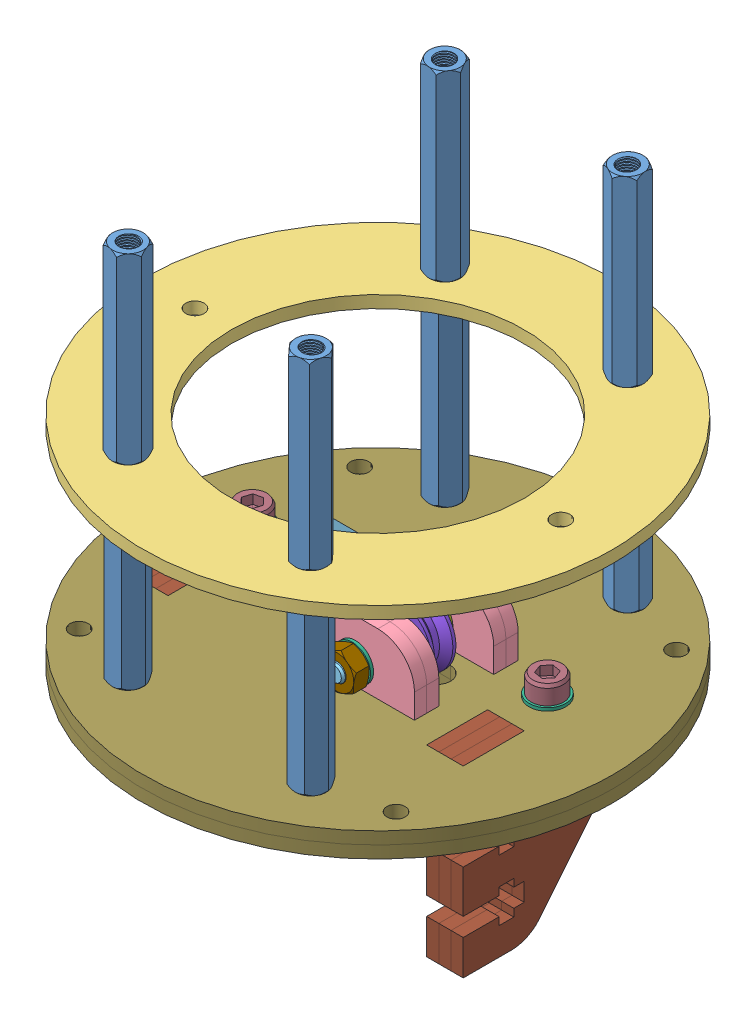
SolidWorks assembly RobotBaseStdServo, configuration Default. Lengths in mm.
Overall size (77 92.39 77).
48 component instances, 14 part files, 113 mates.
Components (placement in the parent):
- M3Spacer30-1: M3Spacer30 [Default] at (-2388.5733 91.3509 1101.0133) size (6.28 30.59 5)
- M3ThreadRod-1: M3ThreadRod [Default] at (-2388.5733 111.8509 1101.0133) x (0.999973 0 0.007408) z (-0.007408 0 0.999973) size (3.13 20.14 3.46)
- MiddlePlate-1: MiddlePlate [Default] at (-2373.5733 123.3509 1075.0326) x (1 0 0) z (0 -1 0) size (77 77 2)
- M3ThreadRod-2: M3ThreadRod [Default] at (-2388.5733 111.8509 1049.0518) x (0.846012 0 -0.533163) z (0.533163 0 0.846012) size (3.13 20.14 3.46)
- M3ThreadRod-3: M3ThreadRod [Default] at (-2358.5733 111.8509 1049.0518) x (-0.305342 0 -0.952243) z (0.952243 0 -0.305342) size (3.13 20.14 3.46)
- M3ThreadRod-4: M3ThreadRod [Default] at (-2358.5733 111.8509 1101.0133) x (0.427939 0 -0.903808) z (0.903808 0 0.427939) size (3.13 20.14 3.46)
- M3Spacer30-2: M3Spacer30 [Default] at (-2358.5733 91.3509 1049.0518) x (0.746598 0 -0.665276) z (0.665276 0 0.746598) size (6.28 30.59 5)
- M3Spacer30-3: M3Spacer30 [Default] at (-2388.5733 91.3509 1049.0518) size (6.28 30.59 5)
- M3Spacer30-4: M3Spacer30 [Default] at (-2358.5733 91.3509 1101.0133) size (6.28 30.59 5)
- M3Spacer30-5: M3Spacer30 [Default] at (-2388.5733 123.3509 1049.0518) x (0.415568 0 0.909562) z (-0.909562 0 0.415568) size (6.28 30.59 5)
- M3Spacer30-6: M3Spacer30 [Default] at (-2358.5733 123.3509 1049.0518) x (0.108158 0 0.994134) z (-0.994134 0 0.108158) size (6.28 30.59 5)
- M3Spacer30-7: M3Spacer30 [Default] at (-2358.5733 123.3509 1101.0133) x (0.980096 0 -0.198526) z (0.198526 0 0.980096) size (6.28 30.59 5)
- M3Spacer30-8: M3Spacer30 [Default] at (-2388.5733 123.3509 1101.0133) x (0.67609 0 -0.736819) z (0.736819 0 0.67609) size (6.28 30.59 5)
- BearingBase-1: BearingBase [Default] at (-2368.7733 94.8509 1083.5326) x (-1 0 0) z (0 0 -1) size (19.4 14 2)
- BearingBase-2: BearingBase [Default] at (-2368.7733 94.8509 1081.5326) x (-1 0 0) z (0 0 -1) size (19.4 14 2)
- BearingBase-3: BearingBase [Default] at (-2368.7733 94.8509 1066.5326) size (19.4 14 2)
- BearingBase-4: BearingBase [Default] at (-2368.7733 94.8509 1068.5326) size (19.4 14 2)
- M3x20-1: M3x20 [Default] at (-2368.7733 94.8509 1066.5326) x (0.029389 0.999568 0) z (-0.999568 0.029389 0) size (5.5 23.77 5.5)
- M3Washer-1: M3Washer [Default] at (-2368.7733 94.8509 1077.5326) x (-0.205267 0.978706 0) z (-0.978706 -0.205267 0) size (6 0.5 6)
- PlasticSpacer-1: PlasticSpacer [Default] at (-2368.7733 94.8509 1070.5326) x (-0.999639 0.026866 0) z (0.026866 0.999639 0) size (6 2 6)
- pulley-1: pulley [Default] at (-2368.7733 94.8509 1073.0326) x (0.617179 0.786823 0) z (0.786823 -0.617179 0) size (12 4 12)
- M3Washer-2: M3Washer [Default] at (-2368.7733 94.8509 1073.0326) x (0.250287 -0.968172 0) z (0.968172 0.250287 0) size (6 0.5 6)
- PlasticSpacer-3: PlasticSpacer [Default] at (-2368.7733 94.8509 1079.5326) x (0.027413 -0.999624 0) z (0.999624 0.027413 0) size (6 2 6)
- M3Nut-1: M3Nut [Default] at (-2368.7733 94.8509 1084.0326) x (-0.925416 -0.378953 0) z (-0.378953 0.925416 0) size (6.35 2.7 5.5)
- M3Washer-4: M3Washer [Default] at (-2388.5733 87.3509 1049.0518) x (-1 0 0) z (0 0 1) size (6 0.5 6)
- M3x10-1: M3x10 [Default] at (-2388.5733 86.8509 1049.0518) x (0.341572 0 -0.939856) z (-0.939856 0 -0.341572) size (5.5 13.21 5.5)
- M3x10-2: M3x10 [Default] at (-2358.5733 86.8509 1049.0518) x (-0.021144 0 0.999776) z (0.999776 0 0.021144) size (5.5 13.21 5.5)
- M3x10-3: M3x10 [Default] at (-2388.5733 86.8509 1101.0133) x (-0.638743 0 0.76942) z (0.76942 0 0.638743) size (5.5 13.21 5.5)
- M3x10-4: M3x10 [Default] at (-2358.5733 86.8509 1101.0133) x (-0.799312 0 0.600916) z (0.600916 0 0.799312) size (5.5 13.21 5.5)
- M3Washer-5: M3Washer [Default] at (-2358.5733 87.3509 1101.0133) x (-1 0 0) z (0 0 1) size (6 0.5 6)
- M3Washer-6: M3Washer [Default] at (-2358.5733 87.3509 1049.0518) x (-1 0 0) z (0 0 1) size (6 0.5 6)
- M3Washer-7: M3Washer [Default] at (-2388.5733 87.3509 1101.0133) x (-1 0 0) z (0 0 1) size (6 0.5 6)
- M3Washer-8: M3Washer [Default] at (-2368.7733 94.8509 1084.0326) x (1 0 0) z (0 1 0) size (6 0.5 6)
- stdServoBase-1: stdServoBase [Default] at (-2350.5733 61.2509 1086.0326) x (0 0 -1) z (1 0 0) size (23 30.1 2)
- stdServoBase-2: stdServoBase [Default] at (-2354.5733 61.2509 1086.0326) x (0 0 -1) z (1 0 0) size (23 30.1 2)
- stdServoBase-3: stdServoBase [Default] at (-2352.5733 61.2509 1086.0326) x (0 0 -1) z (1 0 0) size (23 30.1 2)
- stdServoBase-4: stdServoBase [Default] at (-2398.9733 61.2509 1086.0326) x (0 0 -1) z (1 0 0) size (23 30.1 2)
- M3Nut-2: M3Nut [Default] at (-2351.5733 80.9509 1069.2266) x (-1 0 0) z (0 0 -1) size (6.35 2.7 5.5)
- M3Nut-5: M3Nut [Default] at (-2399.9733 83.4509 1069.2266) x (1 0 0) z (0 0 -1) size (6.35 2.7 5.5)
- M3Washer-13: M3Washer [Default] at (-2351.5733 91.3509 1069.2266) size (6 0.5 6)
- M3Washer-14: M3Washer [Default] at (-2399.9733 91.3509 1069.2266) size (6 0.5 6)
- BottomPlateStdServo-2: BottomPlateStdServo [Default] at (-2373.6467 89.3509 1075.0326) x (1 0 0) z (0 1 0) size (77 77 2)
- BottomPlateStdServo-3: BottomPlateStdServo [Default] at (-2373.6467 87.3509 1075.0326) x (1 0 0) z (0 1 0) size (77 77 2)
- stdServoBase-7: stdServoBase [Default] at (-2402.9733 61.2509 1086.0326) x (0 0 -1) z (1 0 0) size (23 30.1 2)
- stdServoBase-8: stdServoBase [Default] at (-2400.9733 61.2509 1086.0326) x (0 0 -1) z (1 0 0) size (23 30.1 2)
- M3x12-11: M3x12 [Default] at (-2351.5733 94.3509 1069.2266) x (0 -1 0) z (0.637805 0 -0.770198) size (15.11 5.3 5.3)
- M3x12-12: M3x12 [Default] at (-2399.9733 94.3509 1069.2266) x (0 -1 0) z (0.678502 0 0.734599) size (15.11 5.3 5.3)
- PCBMount-1: PCBMount [Default] at (-2380.5233 80.3509 1061.5326) x (-1 0 0) z (0 0 1) size (31.5 14 2)
Mates (geometry in assembly coordinates):
- Concentric1: concentric anti-aligned: circle of M3Spacer30-1; circle of MiddlePlate-1
- Concentric2: concentric anti-aligned: circle of MiddlePlate-1; circle of M3Spacer30-4
- Concentric3: concentric anti-aligned: circle of MiddlePlate-1; circle of M3Spacer30-3
- Concentric4: concentric anti-aligned: circle of MiddlePlate-1; circle of M3Spacer30-2
- Concentric5: concentric aligned: circle of M3ThreadRod-4; circle of M3Spacer30-4
- Concentric7: concentric anti-aligned: circle of M3ThreadRod-3; circle of M3Spacer30-2
- Concentric8: concentric aligned: circle of M3ThreadRod-2; circle of M3Spacer30-3
- Concentric9: concentric aligned: circle of M3Spacer30-1; circle of M3ThreadRod-1
- Distance5: distance = 10 mm aligned: plane of M3ThreadRod-1 through (-2388.5733 131.3509 1101.0133) normal (0 1 0); plane of M3Spacer30-1 through (-2388.5733 121.3509 1101.0133) normal (0 1 0)
- Distance6: distance = 10 mm aligned: plane of M3ThreadRod-2 through (-2388.5733 131.3509 1049.0518) normal (0 1 0); plane of M3Spacer30-3 through (-2388.5733 121.3509 1049.0518) normal (0 1 0)
- Distance7: distance = 10 mm aligned: plane of M3ThreadRod-3 through (-2358.5733 131.3509 1049.0518) normal (0 1 0); plane of M3Spacer30-2 through (-2358.5733 121.3509 1049.0518) normal (0 1 0)
- Distance8: distance = 10 mm aligned: plane of M3ThreadRod-4 through (-2358.5733 131.3509 1101.0133) normal (0 1 0); plane of M3Spacer30-4 through (-2358.5733 121.3509 1101.0133) normal (0 1 0)
- Coincident3: coincident anti-aligned: plane of M3Spacer30-1 through (-2388.5733 121.3509 1101.0133) normal (0 1 0); plane of MiddlePlate-1 through (-2373.5733 121.3509 1075.0326) normal (0 -1 0)
- Coincident4: coincident anti-aligned: plane of MiddlePlate-1 through (-2373.5733 121.3509 1075.0326) normal (0 -1 0); plane of M3Spacer30-4 through (-2358.5733 121.3509 1101.0133) normal (0 1 0)
- Coincident5: coincident anti-aligned: plane of MiddlePlate-1 through (-2373.5733 121.3509 1075.0326) normal (0 -1 0); plane of M3Spacer30-2 through (-2358.5733 121.3509 1049.0518) normal (0 1 0)
- Coincident6: coincident anti-aligned: plane of MiddlePlate-1 through (-2373.5733 121.3509 1075.0326) normal (0 -1 0); plane of M3Spacer30-3 through (-2388.5733 121.3509 1049.0518) normal (0 1 0)
- Concentric10: concentric aligned: circle of M3ThreadRod-2; circle of M3Spacer30-5
- Concentric11: concentric aligned: circle of M3ThreadRod-3; circle of M3Spacer30-6
- Concentric12: concentric aligned: circle of M3ThreadRod-4; circle of M3Spacer30-7
- Concentric13: concentric aligned: circle of M3ThreadRod-1; circle of M3Spacer30-8
- Coincident8: coincident anti-aligned: plane of MiddlePlate-1 through (-2373.5733 123.3509 1075.0326) normal (0 1 0); plane of M3Spacer30-5 through (-2388.5733 123.3509 1049.0518) normal (0 -1 0)
- Coincident9: coincident anti-aligned: plane of MiddlePlate-1 through (-2373.5733 123.3509 1075.0326) normal (0 1 0); plane of M3Spacer30-6 through (-2358.5733 123.3509 1049.0518) normal (0 -1 0)
- Coincident10: coincident anti-aligned: plane of MiddlePlate-1 through (-2373.5733 123.3509 1075.0326) normal (0 1 0); plane of M3Spacer30-7 through (-2358.5733 123.3509 1101.0133) normal (0 -1 0)
- Coincident11: coincident anti-aligned: plane of MiddlePlate-1 through (-2373.5733 123.3509 1075.0326) normal (0 1 0); plane of M3Spacer30-8 through (-2388.5733 123.3509 1101.0133) normal (0 -1 0)
- Parallel8: parallel anti-aligned: plane of BearingBase-1 through (-2372.4733 95.3509 1081.5326) normal (0 0 -1); plane of BearingBase-2 through (-2372.4733 95.3509 1081.5326) normal (0 0 1)
- Coincident74: coincident: point of BearingBase-1; point of BearingBase-2
- Parallel9: parallel anti-aligned: plane of BearingBase-3 through (-2365.0733 95.3509 1068.5326) normal (0 0 1); plane of BearingBase-4 through (-2365.0733 95.3509 1068.5326) normal (0 0 -1)
- Coincident75: coincident: point of BearingBase-3; point of BearingBase-4
- Concentric52: concentric anti-aligned: circle of BearingBase-3; circle of M3x20-1
- Coincident76: coincident anti-aligned: plane of BearingBase-3 through (-2365.0733 95.3509 1066.5326) normal (0 0 -1); plane of M3x20-1 through (-2368.7733 94.8509 1066.5326) normal (0 0 1)
- Concentric55: concentric anti-aligned: circle of M3x20-1; circle of pulley-1
- Coincident79: coincident anti-aligned: plane of pulley-1 through (-2368.7733 94.8509 1073.0326) normal (0 0 -1); plane of M3Washer-2 through (-2368.7733 94.8509 1073.0326) normal (0 0 1)
- Concentric56: concentric anti-aligned: circle of M3Washer-1; circle of pulley-1
- Coincident80: coincident anti-aligned: plane of M3Washer-1 through (-2368.7733 94.8509 1077.0326) normal (0 0 -1); plane of pulley-1 through (-2368.7733 94.8509 1077.0326) normal (0 0 1)
- Concentric58: concentric aligned: circle of BearingBase-2; circle of M3x20-1
- Concentric59: concentric anti-aligned: circle of pulley-1; circle of M3Washer-8
- Coincident83: coincident anti-aligned: plane of BearingBase-1 through (-2372.4733 95.3509 1083.5326) normal (0 0 1); plane of M3Washer-8 through (-2368.7733 94.8509 1083.5326) normal (0 0 -1)
- Concentric60: concentric anti-aligned: circle of M3Nut-1; circle of M3Washer-8
- Coincident84: coincident anti-aligned: plane of M3Nut-1 through (-2368.7733 94.8509 1084.0326) normal (0 0 -1); plane of M3Washer-8 through (-2368.7733 94.8509 1084.0326) normal (0 0 1)
- Concentric61: concentric aligned: circle of PlasticSpacer-1; circle of pulley-1
- Coincident90: coincident anti-aligned: plane of BearingBase-4 through (-2365.0733 95.3509 1070.5326) normal (0 0 1); plane of PlasticSpacer-1 through (-2368.7733 94.8509 1070.5326) normal (0 0 -1)
- Concentric62: concentric anti-aligned: circle of pulley-1; circle of M3Washer-2
- Coincident91: coincident anti-aligned: plane of PlasticSpacer-1 through (-2368.7733 94.8509 1072.5326) normal (0 0 1); plane of M3Washer-2 through (-2368.7733 94.8509 1072.5326) normal (0 0 -1)
- Concentric63: concentric anti-aligned: circle of M3Washer-1; circle of pulley-1
- Concentric64: concentric anti-aligned: circle of pulley-1; circle of PlasticSpacer-3
- Coincident92: coincident anti-aligned: plane of M3Washer-1 through (-2368.7733 94.8509 1077.5326) normal (0 0 1); plane of PlasticSpacer-3 through (-2368.7733 94.8509 1077.5326) normal (0 0 -1)
- Coincident93: coincident anti-aligned: plane of BearingBase-2 through (-2372.4733 95.3509 1079.5326) normal (0 0 -1); plane of PlasticSpacer-3 through (-2368.7733 94.8509 1079.5326) normal (0 0 1)
- Concentric67: concentric aligned: circle of M3x10-4; circle of M3Washer-5
- Coincident95: coincident anti-aligned: plane of M3x10-4 through (-2358.5733 86.8509 1101.0133) normal (0 1 0); plane of M3Washer-5 through (-2358.5733 86.8509 1101.0133) normal (0 -1 0)
- Concentric69: concentric aligned: circle of M3Washer-4; circle of M3x10-1
- Coincident97: coincident anti-aligned: plane of M3Washer-4 through (-2388.5733 86.8509 1049.0518) normal (0 -1 0); plane of M3x10-1 through (-2388.5733 86.8509 1049.0518) normal (0 1 0)
- Concentric71: concentric aligned: circle of M3x10-2; circle of M3Washer-6
- Coincident99: coincident anti-aligned: plane of M3x10-2 through (-2358.5733 86.8509 1049.0518) normal (0 1 0); plane of M3Washer-6 through (-2358.5733 86.8509 1049.0518) normal (0 -1 0)
- Concentric73: concentric aligned: circle of M3x10-3; circle of M3Washer-7
- Coincident101: coincident anti-aligned: plane of M3x10-3 through (-2388.5733 86.8509 1101.0133) normal (0 1 0); plane of M3Washer-7 through (-2388.5733 86.8509 1101.0133) normal (0 -1 0)
- Parallel11: parallel anti-aligned: plane of stdServoBase-1 through (-2350.5733 86.3509 1064.0326) normal (-1 0 0); plane of stdServoBase-3 through (-2350.5733 86.3509 1064.0326) normal (1 0 0)
- Coincident103: coincident: point of stdServoBase-1; point of stdServoBase-3
- Coincident105: coincident: point of stdServoBase-1; point of stdServoBase-3
- Coincident106: coincident: point of stdServoBase-2; point of stdServoBase-3
- Coincident107: coincident: point of stdServoBase-2; point of stdServoBase-3
- Parallel13: parallel anti-aligned: plane of stdServoBase-2 through (-2352.5733 86.3509 1064.0326) normal (1 0 0); plane of stdServoBase-3 through (-2352.5733 86.3509 1064.0326) normal (-1 0 0)
- Coincident119: coincident anti-aligned: plane of stdServoBase-2 through (-2352.5733 81.0509 1071.9766) normal (0 0 -1); plane of M3Nut-2 through (-2353.161 83.4509 1071.9766) normal (0 0 1)
- Coincident120: coincident anti-aligned: plane of stdServoBase-1 through (-2348.5733 83.4509 1067.7266) normal (0 -1 0); plane of M3Nut-2 through (-2351.5733 83.4509 1069.2266) normal (0 1 0)
- Coincident125: coincident anti-aligned: plane of stdServoBase-4 through (-2396.9733 81.0509 1066.4766) normal (0 0 1); plane of M3Nut-5 through (-2401.561 80.9509 1066.4766) normal (0 0 -1)
- Concentric74: concentric aligned: circle of BottomPlateStdServo-2; circle of BottomPlateStdServo-3
- Parallel15: parallel anti-aligned: plane of BottomPlateStdServo-2 through (-2373.5733 89.3509 1075.0326) normal (0 -1 0); plane of BottomPlateStdServo-3 through (-2373.5733 89.3509 1075.0326) normal (0 1 0)
- Concentric75: concentric aligned: circle of BottomPlateStdServo-2; circle of BottomPlateStdServo-3
- Parallel16: parallel anti-aligned: plane of MiddlePlate-1 through (-2373.5733 123.3509 1075.0326) normal (0 1 0); plane of BottomPlateStdServo-3 through (-2373.5733 87.3509 1075.0326) normal (0 -1 0)
- Coincident145: coincident anti-aligned: plane of BearingBase-3 through (-2365.0733 95.3509 1066.5326) normal (0 0 -1); plane of BottomPlateStdServo-2 through (-2363.0733 91.3509 1066.5326) normal (0 0 1)
- Coincident146: coincident anti-aligned: plane of BearingBase-3 through (-2374.4733 87.3509 1068.5326) normal (-1 0 0); plane of BottomPlateStdServo-2 through (-2374.4733 91.3509 1070.5326) normal (1 0 0)
- Coincident155: coincident anti-aligned: plane of stdServoBase-3 through (-2350.5733 80.0009 1086.0326) normal (0 0 1); plane of BottomPlateStdServo-3 through (-2354.5733 89.3509 1086.0326) normal (0 0 -1)
- Coincident156: coincident anti-aligned: plane of stdServoBase-2 through (-2354.5733 86.3509 1064.0326) normal (-1 0 0); plane of BottomPlateStdServo-3 through (-2354.5733 89.3509 1076.0326) normal (1 0 0)
- Parallel17: parallel aligned: plane of stdServoBase-4 through (-2396.9733 86.3509 1064.0326) normal (1 0 0); plane of stdServoBase-8 through (-2398.9733 86.3509 1064.0326) normal (1 0 0)
- Parallel18: parallel aligned: plane of stdServoBase-4 through (-2396.9733 86.3509 1064.0326) normal (1 0 0); plane of stdServoBase-7 through (-2400.9733 86.3509 1064.0326) normal (1 0 0)
- Coincident162: coincident: point of stdServoBase-4; point of stdServoBase-8
- Coincident163: coincident: point of stdServoBase-4; point of stdServoBase-8
- Coincident164: coincident: point of stdServoBase-7; point of stdServoBase-8
- Coincident165: coincident: point of stdServoBase-7; point of stdServoBase-8
- Coincident166: coincident anti-aligned: plane of stdServoBase-4 through (-2396.9733 81.0509 1071.9766) normal (0 0 -1); plane of M3Nut-5 through (-2398.3855 80.9509 1071.9766) normal (0 0 1)
- Coincident167: coincident anti-aligned: plane of stdServoBase-4 through (-2396.9733 83.4509 1071.9766) normal (0 -1 0); plane of M3Nut-5 through (-2399.9733 83.4509 1069.2266) normal (0 1 0)
- Coincident168: coincident anti-aligned: plane of BottomPlateStdServo-3 through (-2402.9733 89.3509 1086.0326) normal (0 0 -1); plane of stdServoBase-8 through (-2398.9733 80.0009 1086.0326) normal (0 0 1)
- Coincident169: coincident anti-aligned: plane of BottomPlateStdServo-3 through (-2402.9733 89.3509 1076.0326) normal (1 0 0); plane of stdServoBase-7 through (-2402.9733 86.3509 1064.0326) normal (-1 0 0)
- Concentric76: concentric aligned: circle of M3Washer-13; circle of BottomPlateStdServo-2
- Concentric77: concentric aligned: circle of M3Washer-14; circle of BottomPlateStdServo-2
- Concentric84: concentric anti-aligned: circle of M3Washer-14; circle of M3x12-12
- Concentric85: concentric anti-aligned: circle of M3Washer-13; circle of M3x12-11
- Coincident171: coincident anti-aligned: plane of BottomPlateStdServo-2 through (-2373.5733 89.3509 1075.0326) normal (0 -1 0); plane of BottomPlateStdServo-3 through (-2373.5733 89.3509 1075.0326) normal (0 1 0)
- Coincident172: coincident: point of BearingBase-1; point of BottomPlateStdServo-3
- Coincident173: coincident anti-aligned: plane of M3Washer-13 through (-2351.5733 91.3509 1069.2266) normal (0 -1 0); plane of BottomPlateStdServo-2 through (-2373.5733 91.3509 1075.0326) normal (0 1 0)
- Coincident174: coincident anti-aligned: plane of M3Washer-14 through (-2399.9733 91.3509 1069.2266) normal (0 -1 0); plane of BottomPlateStdServo-2 through (-2373.5733 91.3509 1075.0326) normal (0 1 0)
- Coincident175: coincident anti-aligned: plane of M3Washer-14 through (-2399.9733 91.8509 1069.2266) normal (0 1 0); plane of M3x12-12 through (-2399.9733 91.8509 1069.2266) normal (0 -1 0)
- Coincident176: coincident anti-aligned: plane of M3Washer-13 through (-2351.5733 91.8509 1069.2266) normal (0 1 0); plane of M3x12-11 through (-2351.5733 91.8509 1069.2266) normal (0 -1 0)
- Coincident177: coincident: point of stdServoBase-1; point of BottomPlateStdServo-2
- Coincident178: coincident: point of BottomPlateStdServo-2; point of stdServoBase-7
- Concentric90: concentric anti-aligned: circle of M3Nut-5; circle of M3x12-12
- Concentric91: concentric aligned: circle of M3Nut-2; circle of M3x12-11
- Parallel19: parallel aligned: plane of MiddlePlate-1 through (-2373.5733 123.3509 1075.0326) normal (0 1 0); plane of BottomPlateStdServo-2 through (-2373.5733 91.3509 1075.0326) normal (0 1 0)
- Concentric92: concentric aligned: circle of M3Spacer30-7; circle of BottomPlateStdServo-2
- Concentric93: concentric aligned: circle of M3Spacer30-8; circle of BottomPlateStdServo-2
- Coincident179: coincident anti-aligned: plane of M3Spacer30-1 through (-2388.5733 91.3509 1101.0133) normal (0 -1 0); plane of BottomPlateStdServo-2 through (-2373.5733 91.3509 1075.0326) normal (0 1 0)
- Concentric94: concentric anti-aligned: circle of M3Washer-5; circle of BottomPlateStdServo-3
- Concentric95: concentric anti-aligned: circle of M3Washer-7; circle of BottomPlateStdServo-3
- Concentric96: concentric anti-aligned: circle of M3Washer-6; circle of BottomPlateStdServo-3
- Concentric97: concentric anti-aligned: circle of M3Washer-4; circle of BottomPlateStdServo-3
- Coincident181: coincident anti-aligned: plane of M3Washer-4 through (-2388.5733 87.3509 1049.0518) normal (0 1 0); plane of BottomPlateStdServo-3 through (-2373.5733 87.3509 1075.0326) normal (0 -1 0)
- Coincident182: coincident anti-aligned: plane of M3Washer-7 through (-2388.5733 87.3509 1101.0133) normal (0 1 0); plane of BottomPlateStdServo-3 through (-2373.5733 87.3509 1075.0326) normal (0 -1 0)
- Coincident183: coincident anti-aligned: plane of M3Washer-5 through (-2358.5733 87.3509 1101.0133) normal (0 1 0); plane of BottomPlateStdServo-3 through (-2373.5733 87.3509 1075.0326) normal (0 -1 0)
- Coincident184: coincident anti-aligned: plane of M3Washer-6 through (-2358.5733 87.3509 1049.0518) normal (0 1 0); plane of BottomPlateStdServo-3 through (-2373.5733 87.3509 1075.0326) normal (0 -1 0)
- Coincident185: coincident aligned: plane of BearingBase-1 through (-2365.0733 101.3509 1081.5326) normal (0 1 0); plane of BearingBase-2 through (-2365.0733 101.3509 1079.5326) normal (0 1 0)
- Coincident186: coincident aligned: plane of BearingBase-1 through (-2374.4733 87.3509 1081.5326) normal (0 -1 0); plane of BearingBase-3 through (-2363.0733 87.3509 1068.5326) normal (0 -1 0)
- Coincident187: coincident aligned: plane of BottomPlateStdServo-2 through (-2373.5733 91.3509 1075.0326) normal (0 1 0); plane of PCBMount-1 through (-2364.7733 91.3509 1063.5326) normal (0 1 0)
- Coincident188: coincident anti-aligned: plane of BottomPlateStdServo-2 through (-2396.2733 91.3509 1063.5326) normal (0 0 -1); plane of PCBMount-1 through (-2368.7733 81.3509 1063.5326) normal (0 0 1)
- Coincident189: coincident anti-aligned: plane of BottomPlateStdServo-3 through (-2396.2733 89.3509 1061.5326) normal (1 0 0); plane of PCBMount-1 through (-2396.2733 81.3509 1063.5326) normal (-1 0 0)
